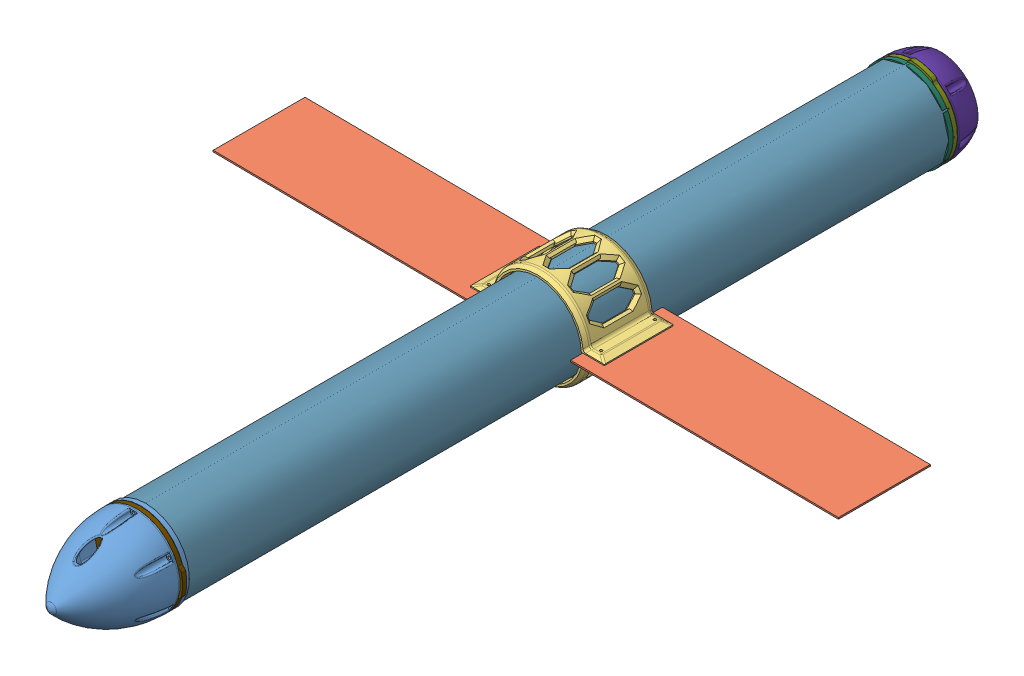
SolidWorks assembly Albatross_Assembly, configuration Default. Lengths in mm.
Overall size (816.95 156.14 1165.13).
121 component instances, 57 part files, 36 mates.
Components (placement in the parent):
- Front_WTE4-M-FLANGE-SEAL-R2-1: Front_WTE4-M-FLANGE-SEAL-R2 [默认] at (338.1764 686.4065 1049.3568) size (114.3 114.3 27.53)
- Main Ballast Tank-1: Main Ballast Tank [Default] at (332.7763 642.9544 942.3173) size (104.09 101.96 419.5)
  - Engine_endcap_mount-1: Engine_endcap_mount [默认] at (605.4001 -106.548 107.0395) x (-1 0 0) z (0 0 -1) size (100 100 15)
  - Engine_end_connector-1: Engine_end_connector [默认] at (-444.5999 -106.548 75.0395) size (100 100 25)
  - Syringe_clamp_front-2: Syringe_clamp_front [默认] at (155.4001 -106.548 75.0395) x (-1 0 0) z (0 0 -1) size (100 100 20)
  - Syringe_clamp_back-1: Syringe_clamp_back [默认] at (-144.5999 43.452 -49.0312) size (100 100 20)
  - Syringe_plunger_back-1: Syringe_plunger_back [默认] at (305.4001 43.452 -112.9677) x (-1 0 0) z (0 0 -1) size (100 98.49 25)
  - Buoyancy_engine_bearing_plate-1: Buoyancy_engine_bearing_plate [默认] at (155.3708 46.4151 -307.9605) x (0.999805 0.019754 0) z (0 0 1) size (100 100 25)
  - Buoyancy_engine_motor_mount-1: Buoyancy_engine_motor_mount [默认] at (308.3047 -100.5925 -209.9605) x (-0.999805 -0.019754 0) z (0 0 -1) size (100 100 20)
  - 8mm_acme_300mm-1: 8mm_acme_300mm [默认] at (-114.5999 43.452 109.0395) x (1 0 0) z (0 -1 0) size (9.24 302.5 8)
  - 8mm_smooth_rod_330mm-1: 8mm_smooth_rod_330mm [默认] at (-93.7998 2.9599 100.0395) x (1 0 0) z (0 -1 0) size (8 330 8)
  - Syringe_barrel-1: Syringe_barrel [默认] at (-27.5999 43.452 -44.0312) x (1 0 0) z (0 -1 0) size (31.2 149 31.2)
  - Syringe_plunger-1: Syringe_plunger [默认] at (-27.4985 43.188 -112.9677) x (0.913504 -0.40683 0) z (-0.40683 -0.913504 0) size (29 126.4 29)
  - Syringe_plunger_rubber-1: Syringe_plunger_rubber [默认] at (-27.2521 42.5347 4.7123) x (1 0 0) z (0 0 -1) size (29.91 29.91 12.8)
  - Syringe_plunger_rubber-2: Syringe_plunger_rubber [默认] at (-11.3881 71.0792 4.7123) x (0.5 -0.866025 0) z (0 0 -1) size (29.91 29.91 12.8)
  - Syringe_plunger_rubber-3: Syringe_plunger_rubber [默认] at (21.2641 71.6127 4.7123) x (-0.5 -0.866025 0) z (0 0 -1) size (29.91 29.91 12.8)
  - Syringe_plunger_rubber-4: Syringe_plunger_rubber [默认] at (38.0523 43.6019 4.7123) x (-1 0 0) z (0 0 -1) size (29.91 29.91 12.8)
  - Syringe_plunger_rubber-5: Syringe_plunger_rubber [默认] at (22.1883 15.0574 4.7123) x (-0.5 0.866025 0) z (0 0 -1) size (29.91 29.91 12.8)
  - Syringe_plunger_rubber-6: Syringe_plunger_rubber [默认] at (-10.4639 14.5239 4.7123) x (0.5 0.866025 0) z (0 0 -1) size (29.91 29.91 12.8)
  - Syringe_plunger-2: Syringe_plunger [默认] at (-10.9456 71.6192 -112.9677) x (0.104427 -0.994533 0) z (-0.994533 -0.104427 0) size (29 126.4 29)
  - Syringe_plunger-3: Syringe_plunger [默认] at (21.9531 71.4995 -112.9677) x (-0.809077 -0.587702 0) z (-0.587702 0.809077 0) size (29 126.4 29)
  - Syringe_plunger-4: Syringe_plunger [默认] at (38.2988 42.9486 -112.9677) x (-0.913504 0.40683 0) z (0.40683 0.913504 0) size (29 126.4 29)
  - Syringe_plunger-5: Syringe_plunger [默认] at (21.7458 14.5174 -112.9677) x (-0.104427 0.994533 0) z (0.994533 0.104427 0) size (29 126.4 29)
  - Syringe_plunger-6: Syringe_plunger [默认] at (-11.1528 14.637 -112.9677) x (0.809077 0.587702 0) z (0.587702 -0.809077 0) size (29 126.4 29)
  - Syringe_barrel-2: Syringe_barrel [默认] at (-10.7676 71.839 -44.0312) x (0.5 -0.866025 0) z (-0.866025 -0.5 0) size (31.2 149 31.2)
  - Syringe_barrel-3: Syringe_barrel [默认] at (22.2324 71.4553 -44.0312) x (-0.5 -0.866025 0) z (-0.866025 0.5 0) size (31.2 149 31.2)
  - Syringe_barrel-4: Syringe_barrel [默认] at (38.4001 42.6846 -44.0312) x (-1 0 0) z (0 1 0) size (31.2 149 31.2)
  - Syringe_barrel-5: Syringe_barrel [默认] at (21.5678 14.2976 -44.0312) x (-0.5 0.866025 0) z (0.866025 0.5 0) size (31.2 149 31.2)
  - Syringe_barrel-6: Syringe_barrel [默认] at (-11.4322 14.6813 -44.0312) x (0.5 0.866025 0) z (0.866025 -0.5 0) size (31.2 149 31.2)
  - LM8UU-1: LM8UU [默认] at (40.4741 123.702 -137.9677) x (0 1 0) z (1 0 0) size (15 24 15)
  - LM8UU-2: LM8UU [默认] at (-81.6354 33.702 -137.9677) x (-0.866025 -0.5 0) z (-0.5 0.866025 0) size (15 24 15)
  - LM8UU-3: LM8UU [默认] at (57.3616 -27.048 -137.9677) x (0.866025 -0.5 0) z (-0.5 -0.866025 0) size (15 24 15)
  - 4mm_threaded_rod_300mm-1: 4mm_threaded_rod_300mm [默认] at (5.4064 -111.548 85.0395) x (0 1 0) z (1 0 0) size (4 300 4)
  - 4mm_threaded_rod_300mm-2: 4mm_threaded_rod_300mm [默认] at (139.6309 120.9575 85.0395) x (-0.866025 -0.5 0) z (-0.5 0.866025 0) size (4 300 4)
  - 4mm_threaded_rod_300mm-3: 4mm_threaded_rod_300mm [默认] at (-128.837 120.9466 85.0395) x (0.866025 -0.5 0) z (-0.5 -0.866025 0) size (4 300 4)
  - motors_17_42_60mm-1: motors_17_42_60mm [默认] at (5.4001 43.452 -269.9605) size (42.3 42.3 84)
  - 8mm_smooth_rod_330mm-2: 8mm_smooth_rod_330mm [默认] at (90.0673 -22.2116 100.0395) x (-0.5 0.866025 0) z (0.866025 0.5 0) size (8 330 8)
  - 8mm_smooth_rod_330mm-3: 8mm_smooth_rod_330mm [默认] at (19.9329 149.6078 100.0395) x (-0.5 -0.866025 0) z (-0.866025 0.5 0) size (8 330 8)
  - Chassis_beam_buoyancy_engine-1: Chassis_beam_buoyancy_engine [默认] at (947.4909 -422.5422 -306.9605) x (-0.875733 0.482795 0) z (0.482795 0.875733 0) size (10 96 5)
  - Chassis_beam_buoyancy_engine-2: Chassis_beam_buoyancy_engine [默认] at (-936.6906 509.4462 -306.9605) x (0.875733 -0.482795 0) z (-0.482795 -0.875733 0) size (10 96 5)
  - Chassis_beam_buoyancy_engine-3: Chassis_beam_buoyancy_engine [默认] at (880.0083 626.3294 -306.9605) x (-0.855979 -0.51701 0) z (-0.51701 0.855979 0) size (10 96 5)
  - Chassis_beam_buoyancy_engine-4: Chassis_beam_buoyancy_engine [默认] at (-869.2081 -539.4254 -306.9605) x (0.855979 0.51701 0) z (0.51701 -0.855979 0) size (10 96 5)
  - Coupling_19_25_5_8mm-1: Coupling_19_25_5_8mm [默认] at (5.3281 43.4517 -198.9605) x (0.713357 0.700801 0) z (0.700801 -0.713357 0) size (20 25 19.06)
  - Screw nut_8mm-1: Screw nut_8mm [默认] at (5.3281 43.4517 -120.9677) x (0.009005 -0.999959 0) z (-0.999959 -0.009005 0) size (22 15 22)
- Adjustment cabin-1: Adjustment cabin [默认] at (338.4472 690.1304 520.8568) size (100 100 340)
  - Pogo_header_front_mount-1: Pogo_header_front_mount [默认] at (299.7292 -3.7239 87.5) size (100 100 25)
  - F8-16M-1: F8-16M [默认] at (119.7292 -3.7239 108.5) x (1 0 0) z (0 -1 0) size (16 5 16)
  - M8_bolt_40mm-2: M8_bolt_40mm [默认] at (-30.2708 -3.7239 78.5) x (1 0 0) z (0 -1 0) size (13 44 13)
  - F8-16M-2: F8-16M [默认] at (119.7292 -3.7239 82.5) x (1 0 0) z (0 -1 0) size (16 5 16)
  - LM8UU-1: LM8UU [默认] at (25.9542 15.7761 88.5) x (1 0 0) z (0 -1 0) size (15 24 15)
  - LM8UU-2: LM8UU [默认] at (3.5042 -36.1854 88.5) x (-0.5 -0.866025 0) z (-0.866025 0.5 0) size (15 24 15)
  - LM8UU-3: LM8UU [默认] at (-30.2708 9.2376 88.5) x (-0.5 0.866025 0) z (0.866025 0.5 0) size (15 24 15)
  - Pogo_header_slider_mount-1: Pogo_header_slider_mount [默认] at (-300.2708 -153.7239 73.6245) x (-1 0 0) z (0 0 -1) size (98 93.03 21)
  - 8mm_smooth_rod_45mm-1: 8mm_smooth_rod_45mm [默认] at (-26.4958 15.7761 98.6245) x (1 0 0) z (0 -1 0) size (8 45 8)
  - 8mm_smooth_rod_45mm-2: 8mm_smooth_rod_45mm [默认] at (-4.0458 -36.1854 98.6245) x (-0.5 0.866025 0) z (0.866025 0.5 0) size (8 45 8)
  - 8mm_smooth_rod_45mm-3: 8mm_smooth_rod_45mm [默认] at (29.7292 9.2376 98.6245) x (-0.5 -0.866025 0) z (-0.866025 0.5 0) size (8 45 8)
  - Pogo_header_back_mount-2: Pogo_header_back_mount [默认] at (-449.7708 32.2761 73.6245) x (-1 0 0) z (0 0 -1) size (42 26 50)
  - Acme_bearing_back-2: Acme_bearing_back [默认] at (-450.2708 -153.7239 68.6245) x (-1 0 0) z (0 0 -1) size (36.44 35.5 10)
  - 608ZZ-1: 608ZZ [默认] at (-30.2708 -3.7239 55.6245) x (-1 0 0) z (0 1 0) size (22 7 22)
  - Acme_bearing_front-1: Acme_bearing_front [默认] at (-450.2708 -303.7239 55.6245) x (-1 0 0) z (0 0 -1) size (36.44 35.5 16)
  - Battery_mount_bearings-1: Battery_mount_bearings [默认] at (-0.2708 -3.7239 -6.0228) x (-1 0 0) z (0 0 -1) size (98 69.8 25)
  - Battery_mount_acme-1: Battery_mount_acme [默认] at (-0.2708 -153.7239 -97.0228) size (98 69.8 40)
  - Battery_rods_cover-1: Battery_rods_cover [默认] at (599.7292 -3.7239 -98.0228) size (98 58 1)
  - Battery_mount_connector-1: Battery_mount_connector [默认] at (150.2292 11.2761 98.4772) x (1 0 0) z (0 1 0) size (50 91 30)
  - LM8UU-4: LM8UU [默认] at (79.7292 6.2761 -31.0228) x (1 0 0) z (0 -1 0) size (15 24 15)
  - LM8UU-5: LM8UU [默认] at (39.7292 6.2761 -31.0228) x (1 0 0) z (0 -1 0) size (15 24 15)
  - 18650-1: 18650 [默认] at (-30.2708 -3.7239 -77.0228) x (1 0 0) z (0 -1 0) size (18 68 18)
  - 18650-7: 18650 [默认] at (-26.2516 11.2761 -77.0228) x (0.866025 -0.5 0) z (-0.5 -0.866025 0) size (18 68 18)
  - 18650-8: 18650 [默认] at (-15.2708 22.2569 -77.0228) x (0.5 -0.866025 0) z (-0.866025 -0.5 0) size (18 68 18)
  - 18650-9: 18650 [默认] at (-0.2708 26.2761 -77.0228) x (0 -1 0) z (-1 0 0) size (18 68 18)
  - 18650-10: 18650 [默认] at (14.7292 22.2569 -77.0228) x (-0.5 -0.866025 0) z (-0.866025 0.5 0) size (18 68 18)
  - 18650-11: 18650 [默认] at (25.7099 11.2761 -77.0228) x (-0.866025 -0.5 0) z (-0.5 0.866025 0) size (18 68 18)
  - 18650-12: 18650 [默认] at (29.7292 -3.7239 -77.0228) x (-1 0 0) z (0 1 0) size (18 68 18)
  - Pitch_motor_mount-1: Pitch_motor_mount [默认] at (149.7292 -303.7239 -157.5) size (98 97.69 35)
  - motors_17_42_34mm-1: motors_17_42_34mm [默认] at (-56.8394 52.8447 -186.5) x (0.707107 -0.707107 0) z (0 0 1) size (42.3 42.3 58)
  - 8mm_rod_90mm-1: 8mm_rod_90mm [默认] at (-96.2708 -9.2239 -6.0228) x (1 0 0) z (0 -1 0) size (8 90 8)
  - 8mm_rod_90mm-11: 8mm_rod_90mm [默认] at (-106.2708 -9.2239 -6.0228) x (1 0 0) z (0 -1 0) size (8 90 8)
  - 8mm_rod_90mm-12: 8mm_rod_90mm [默认] at (-100.2708 -17.7239 -6.0228) x (1 0 0) z (0 -1 0) size (8 90 8)
  - 8mm_rod_90mm-15: 8mm_rod_90mm [默认] at (-80.2708 -19.7239 -6.0228) x (1 0 0) z (0 -1 0) size (8 90 8)
  - 8mm_rod_90mm-16: 8mm_rod_90mm [默认] at (-96.7708 -26.7239 -6.0228) x (1 0 0) z (0 -1 0) size (8 90 8)
  - 8mm_rod_90mm-17: 8mm_rod_90mm [默认] at (-86.7708 -26.7239 -6.0228) x (1 0 0) z (0 -1 0) size (8 90 8)
  - 8mm_rod_90mm-18: 8mm_rod_90mm [默认] at (-90.2708 -17.7239 -6.0228) x (1 0 0) z (0 -1 0) size (8 90 8)
  - 8mm_rod_90mm-19: 8mm_rod_90mm [默认] at (95.7292 -9.2239 -6.0228) x (-1 0 0) z (0 1 0) size (8 90 8)
  - 8mm_rod_90mm-20: 8mm_rod_90mm [默认] at (99.7292 -17.7239 -6.0228) x (-1 0 0) z (0 1 0) size (8 90 8)
  - 8mm_rod_90mm-21: 8mm_rod_90mm [默认] at (96.2292 -26.7239 -6.0228) x (-1 0 0) z (0 1 0) size (8 90 8)
  - 8mm_rod_90mm-22: 8mm_rod_90mm [默认] at (86.2292 -26.7239 -6.0228) x (-1 0 0) z (0 1 0) size (8 90 8)
  - 8mm_rod_90mm-23: 8mm_rod_90mm [默认] at (79.7292 -19.7239 -6.0228) x (-1 0 0) z (0 1 0) size (8 90 8)
  - 8mm_rod_90mm-24: 8mm_rod_90mm [默认] at (105.7292 -9.2239 -6.0228) x (-1 0 0) z (0 1 0) size (8 90 8)
  - 8mm_rod_90mm-25: 8mm_rod_90mm [默认] at (89.7292 -17.7239 -6.0228) x (-1 0 0) z (0 1 0) size (8 90 8)
  - 8mm_smooth_rod_245mm-1: 8mm_smooth_rod_245mm [默认] at (-180.2708 6.2761 87.5) x (1 0 0) z (0 -1 0) size (8 245 8)
  - 8mm_smooth_rod_245mm-2: 8mm_smooth_rod_245mm [默认] at (-140.2708 6.2761 87.5) x (1 0 0) z (0 -1 0) size (8 245 8)
  - 8mm_acme_215mm-1: 8mm_acme_215mm [默认] at (-180.2708 -3.7239 81.5) x (1 0 0) z (0 -1 0) size (9.24 218.8 8)
  - Coupling_19_25_5_8mm-1: Coupling_19_25_5_8mm [默认] at (-0.2708 -3.7239 -141.5) x (1 0 0) z (0 -1 0) size (20 25 19.06)
  - 8mm_threaded_rod_105mm-1: 8mm_threaded_rod_105mm [默认] at (-140.2708 -33.7239 -6.0228) x (1 0 0) z (0 -1 0) size (8 105 8)
  - Pitch_motor_back_plate-1: Pitch_motor_back_plate [默认] at (299.7292 -303.7239 -217.5) size (98 83.69 20)
  - Chassis_beam_middle-1: Chassis_beam_middle [默认] at (41.4188 12.6232 -216.5) x (0.258819 -0.965926 0) z (0 0 1) size (10 5.25 83)
  - Chassis_beam_middle-2: Chassis_beam_middle [默认] at (4.7292 -48.2239 -216.5) x (-1 0 0) z (0 0 1) size (10 5.25 83)
  - Chassis_beam_middle-3: Chassis_beam_middle [默认] at (-44.5486 2.9639 -216.5) x (0.258819 0.965926 0) z (0 0 1) size (10 5.25 83)
  - Screw nut_8mm-1: Screw nut_8mm [默认] at (-0.2708 -3.7239 -97.0228) x (0.707107 -0.707107 0) z (-0.707107 -0.707107 0) size (22 15 22)
- Control cabin-1: Control cabin [默认] at (239.0054 696.2498 279.339) x (1 0 0) z (0 -0.008727 0.999962) size (100 99.87 204.47)
  - parts_rough-2: parts_rough [默认] at (99.171 -9.6682 20.1029) x (-1 0 0) z (0 0.999962 -0.008727) size (100 30 87.5)
  - Roll_motor_mount-1: Roll_motor_mount [默认] at (999.171 -309.9186 -7.278) x (-1 0 0) z (0 -0.008727 -0.999962) size (100 84.7 20)
  - motors_17_42_34mm-1: motors_17_42_34mm [默认] at (19.171 -10.2267 -43.8947) x (1 0 0) z (0 0.008727 0.999962) size (42.3 42.3 58)
  - Circuit_rack_end-1: Circuit_rack_end [默认] at (849.171 -310.7243 -99.5995) x (-1 0 0) z (0 -0.008727 -0.999962) size (100 70.66 20)
  - Circuit_rack_endcap_mount-1: Circuit_rack_endcap_mount [默认] at (-350.829 -311.4021 -177.2715) x (1 0 0) z (0 0.008727 0.999962) size (100 99.7 20)
  - Control_board-1: Control_board [默认] at (141.716 -33.1654 -105.5219) x (-1 0 0) z (0 -0.999962 0.008727) size (85.09 66.67 20.6)
  - Fathom-S_mounting_bracket-1: Fathom-S_mounting_bracket [默认] at (849.171 -22.2567 -138.9558) x (-1 0 0) z (0 -0.999962 0.008727) size (97.61 66.67 11)
  - Chassis_beam_PCB_mount-1: Chassis_beam_PCB_mount [默认] at (-137.7847 1054.984 -19.6894) x (0.258819 -0.965889 0.008429) z (0.965926 0.258809 -0.002259) size (10 169 5)
  - Chassis_beam_PCB_mount-2: Chassis_beam_PCB_mount [默认] at (1189.171 -56.6826 -9.988) x (-1 0 0) z (0 -0.999962 0.008727) size (10 169 5)
  - Chassis_beam_PCB_mount-3: Chassis_beam_PCB_mount [默认] at (-228.0988 -1050.6541 -1.3137) x (0.258819 0.965889 -0.008429) z (-0.965926 0.258809 -0.002259) size (10 169 5)
  - F4-9M-1: F4-9M [默认] at (189.171 -9.6333 24.1027) x (1 0 0) z (0 0.999962 -0.008727) size (9 4 9)
- Round tube-3: Round tube [默认] at (338.1764 686.4065 545.3568) size (114.3 114.3 1000)
- Back_WTE4-M-FLANGE-SEAL-R2-1: Back_WTE4-M-FLANGE-SEAL-R2 [默认] at (338.1764 686.4065 99.3568) x (-1 0 0) z (0 0 -1) size (114.3 114.3 27.53)
- Rear_end_cap-1: Rear_end_cap [默认] at (338.1764 686.4065 66.3568) x (0.866025 0.5 0) z (0 0 1) size (114.3 114.3 6)
- Tail_endcap_shroud-2: Tail_endcap_shroud [默认] at (1023.7979 347.4033 66.3568) x (-0.965926 0.258819 0) z (0 0 -1) size (117.59 114.3 35)
- Front_end_cap-1: Front_end_cap [默认] at (338.1764 686.4065 1076.3568) size (120.3 114.3 6)
- Nosecone-1: Nosecone [默认] at (-261.8236 686.4065 1082.3568) size (114.3 120.64 114.13)
- Wings-1: Wings [默认] at (104.7092 688.9439 513.6971) x (0 0 -1) z (-0.008727 -0.999962 0) size (120 350 2)
- Wing_mount-1: Wing_mount [默认] at (935.5356 381.182 468.6971) x (0.999962 -0.008727 0) z (0 0 1) size (174.96 62 90)
- Wing_mount-2: Wing_mount [默认] at (-259.1828 991.631 468.6971) x (-0.999962 0.008727 0) z (0 0 1) size (174.96 62 90)
- Wings-2: Wings [默认] at (571.6348 682.8691 513.6971) x (0 0 -1) z (0.008727 0.999962 0) size (120 350 2)
Mates (geometry in assembly coordinates):
- 同心2: concentric anti-aligned: cylinder of ? through (338.1764 686.4065 1083.3568) axis (0 0 -1) radius 50.8; cylinder of Front_WTE4-M-FLANGE-SEAL-R2-1 through (338.1764 686.4065 1089.3568) axis (0 0 1) radius 44.419
- 重合1: coincident anti-aligned: plane of ? through (395.3264 686.4065 1083.3568) normal (0 0 1); plane of Front_WTE4-M-FLANGE-SEAL-R2-1 through (388.5954 686.4065 1083.3568) normal (0 0 -1)
- 同心3: concentric anti-aligned: cylinder of ? through (338.1764 686.4065 1083.3568) axis (0 0 -1) radius 57.15; cylinder of Main Ballast Tank-1/Engine_endcap_mount-1 through (338.1764 686.4065 1055.3568) axis (0 0 1) radius 50
- 重合2: coincident anti-aligned: plane of Front_WTE4-M-FLANGE-SEAL-R2-1 through (338.1764 686.4065 1049.3568) normal (0 0 -1); plane of Main Ballast Tank-1/Engine_endcap_mount-1 through (338.1764 686.4065 1049.3568) normal (0 0 1)
- 重合3: coincident anti-aligned: cylinder of Main Ballast Tank-1/Buoyancy_engine_bearing_plate-1 through (338.1764 686.4065 634.3568) axis (0 0 1) radius 50; circle of Adjustment cabin-1/Pogo_header_front_mount-1
- 重合4: coincident anti-aligned: plane of Main Ballast Tank-1/Buoyancy_engine_bearing_plate-1 through (338.1764 686.4065 634.3568) normal (0 0 -1); plane of Adjustment cabin-1/F8-16M-1 through (346.1764 686.4065 634.3568) normal (0 0 1)
- 同心4: concentric aligned: cylinder of Adjustment cabin-1/Pitch_motor_back_plate-1 through (338.1764 686.4065 308.3568) axis (0 0 -1) radius 49; cylinder of Control cabin-1/parts_rough-2 through (338.1764 686.4065 299.3568) axis (0 0 -1) radius 50
- 同心5: concentric anti-aligned: cylinder of Adjustment cabin-1/Pitch_motor_back_plate-1 through (338.1764 686.4065 308.3568) axis (0 0 -1) radius 4.1; cylinder of Control cabin-1/parts_rough-2 through (338.1764 686.4065 299.3568) axis (0 0 1) radius 2.5
- 同心6: concentric aligned: cylinder of Front_WTE4-M-FLANGE-SEAL-R2-1 through (338.1764 686.4065 1076.8835) axis (0 0 -1) radius 50.419; cylinder of Round tube-3 through (338.1764 686.4065 1020.3568) axis (0 0 -1) radius 57.15
- 重合5: coincident anti-aligned: plane of Front_WTE4-M-FLANGE-SEAL-R2-1 through (388.5954 686.4065 1070.3568) normal (0 0 -1); plane of Round tube-3 through (395.3264 686.4065 1070.3568) normal (0 0 1)
- 重合6: coincident anti-aligned: plane of Adjustment cabin-1/Pitch_motor_back_plate-1 through (918.6783 666.4065 303.3568) normal (0 0 -1); plane of Control cabin-1/F4-9M-1 through (340.1764 686.4065 303.3568) normal (0 0 1)
- 同心7: concentric anti-aligned: cylinder of Control cabin-1/Circuit_rack_endcap_mount-1 through (338.1764 686.4065 107.7155) axis (0 0 -1) radius 50; cylinder of Back_WTE4-M-FLANGE-SEAL-R2-1 through (338.1764 686.4065 71.8301) axis (0 0 1) radius 57.15
- 平行1: parallel anti-aligned: cylinder of Control cabin-1/Circuit_rack_endcap_mount-1 through (371.4104 719.6405 99.3568) axis (0 0 -1) radius 1.8; cylinder of Back_WTE4-M-FLANGE-SEAL-R2-1 through (371.4033 719.6334 99.3568) axis (0 0 1) radius 1.3
- 重合7: coincident anti-aligned: plane of Control cabin-1/Circuit_rack_endcap_mount-1 through (338.1764 636.4065 99.3568) normal (0 0 -1); plane of Back_WTE4-M-FLANGE-SEAL-R2-1 through (338.1764 686.4065 99.3568) normal (0 0 1)
- 同心11: concentric anti-aligned: cylinder of Back_WTE4-M-FLANGE-SEAL-R2-1 through (338.1764 686.4065 71.8301) axis (0 0 1) radius 57.15; cylinder of Rear_end_cap-1 through (338.1764 686.4065 72.3568) axis (0 0 -1) radius 57.15
- 同心12: concentric anti-aligned: cylinder of Back_WTE4-M-FLANGE-SEAL-R2-1 through (324.2066 738.5423 78.3568) axis (0 0 1) radius 1.3; cylinder of Rear_end_cap-1 through (324.2066 738.5423 66.3568) axis (0 0 -1) radius 1.6
- 同心13: concentric anti-aligned: cylinder of Back_WTE4-M-FLANGE-SEAL-R2-1 through (376.3425 724.5726 78.3568) axis (0 0 1) radius 1.3; cylinder of Rear_end_cap-1 through (376.3425 724.5726 66.3568) axis (0 0 -1) radius 1.6
- 重合8: coincident anti-aligned: plane of Back_WTE4-M-FLANGE-SEAL-R2-1 through (281.0264 686.4065 72.3568) normal (0 0 -1); plane of Rear_end_cap-1 through (338.1764 686.4065 72.3568) normal (0 0 1)
- 重合9: coincident anti-aligned: cylinder of Rear_end_cap-1 through (338.1764 686.4065 72.3568) axis (0 0 -1) radius 57.15; circle of Tail_endcap_shroud-2
- 同心14: concentric aligned: cylinder of Rear_end_cap-1 through (376.3425 724.5726 66.3568) axis (0 0 -1) radius 1.6; cylinder of Tail_endcap_shroud-2 through (376.3425 724.5726 34.1262) axis (0 0 -1) radius 1.8
- 重合10: coincident anti-aligned: plane of Rear_end_cap-1 through (338.1764 686.4065 66.3568) normal (0 0 -1); plane of Tail_endcap_shroud-2 through (338.1764 686.4065 66.3568) normal (0 0 1)
- 同心15: concentric anti-aligned: cylinder of Front_WTE4-M-FLANGE-SEAL-R2-1 through (338.1764 686.4065 1076.8835) axis (0 0 -1) radius 57.15; cylinder of Front_end_cap-1 through (338.1764 686.4065 1076.3568) axis (0 0 1) radius 57.15
- 同心16: concentric aligned: cylinder of Front_WTE4-M-FLANGE-SEAL-R2-1 through (384.9201 713.394 1070.3568) axis (0 0 -1) radius 1.3; cylinder of Front_end_cap-1 through (384.9201 713.394 1076.3568) axis (0 0 -1) radius 1.6
- 同心17: concentric aligned: cylinder of Front_WTE4-M-FLANGE-SEAL-R2-1 through (291.4327 659.419 1070.3568) axis (0 0 -1) radius 1.3; cylinder of Front_end_cap-1 through (291.4327 659.419 1076.3568) axis (0 0 -1) radius 1.6
- 重合11: coincident anti-aligned: plane of Front_WTE4-M-FLANGE-SEAL-R2-1 through (395.3264 686.4065 1076.3568) normal (0 0 1); plane of Front_end_cap-1 through (338.1764 686.4065 1076.3568) normal (0 0 -1)
- 同心18: concentric anti-aligned: cylinder of Front_end_cap-1 through (338.1764 686.4065 1076.3568) axis (0 0 1) radius 57.15; cylinder of Nosecone-1 through (338.1764 686.4065 1141.0973) axis (0 0 -1) radius 57.15
- 同心19: concentric aligned: cylinder of Front_end_cap-1 through (338.1764 740.3815 1076.3568) axis (0 0 -1) radius 1.6; cylinder of Nosecone-1 through (338.1764 740.3815 1082.3568) axis (0 0 -1) radius 1.8
- 重合12: coincident anti-aligned: plane of Front_end_cap-1 through (338.1764 686.4065 1082.3568) normal (0 0 1); plane of Nosecone-1 through (338.1764 632.8315 1082.3568) normal (0 0 -1)
- 同心20: concentric anti-aligned: cylinder of Round tube-3 through (338.1764 686.4065 1020.3568) axis (0 0 -1) radius 57.15; cylinder of Wing_mount-1 through (338.1764 686.4065 558.6971) axis (0 0 1) radius 57.5
- 同心21: concentric anti-aligned: cylinder of Round tube-3 through (338.1764 686.4065 1020.3568) axis (0 0 -1) radius 57.15; cylinder of Wing_mount-2 through (338.1764 686.4065 558.6971) axis (0 0 1) radius 57.5
- 同心23: concentric aligned: circle of Wings-1; cylinder of Wing_mount-2 through (264.642 680.5479 478.6971) axis (-0.008727 -0.999962 0) radius 1.7
- 同心24: concentric aligned: cylinder of Wings-1 through (264.7031 687.5477 548.6971) axis (-0.008727 -0.999962 0) radius 1.5; cylinder of Wing_mount-2 through (264.642 680.5479 548.6971) axis (-0.008727 -0.999962 0) radius 1.7
- 重合13: coincident anti-aligned: plane of Wings-1 through (104.6918 686.944 513.6971) normal (-0.008727 -0.999962 0); plane of Wing_mount-2 through (410.641 684.274 513.6971) normal (0.008727 0.999962 0)
- 同心25: concentric anti-aligned: cylinder of Wing_mount-2 through (411.5973 679.2655 548.6971) axis (-0.008727 -0.999962 0) radius 1.7; cylinder of Wings-2 through (411.6409 684.2653 548.6971) axis (0.008727 0.999962 0) radius 1.5
- 重合14: coincident anti-aligned: plane of Wing_mount-2 through (410.641 684.274 513.6971) normal (0.008727 0.999962 0); plane of Wings-2 through (571.6348 682.8691 513.6971) normal (-0.008727 -0.999962 0)
- 同心26: concentric anti-aligned: cylinder of Wings-1 through (264.7031 687.5477 548.6971) axis (-0.008727 -0.999962 0) radius 1.5; cylinder of Wing_mount-1 through (264.7555 693.5475 548.6971) axis (0.008727 0.999962 0) radius 1.7
